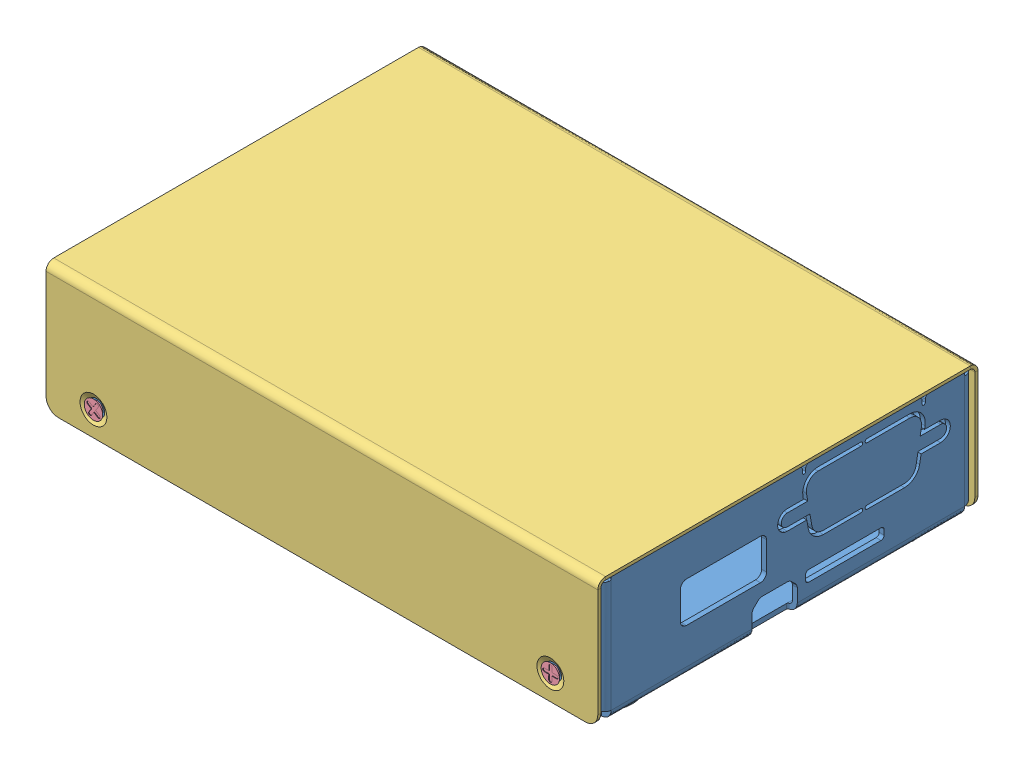
SolidWorks assembly BB100_assembly, configuration Default. Lengths in mm.
Overall size (89.98 22.52 61.99).
15 component instances, 5 part files, 15 mates.
Components (placement in the parent):
- Chassis_bottom_assembly-1: Chassis_bottom_assembly [Default] at (37.4875 44.5592 71.6982) size (89.97 20.42 60.79)
  - Chassis_bottom-1: Chassis_bottom [Default] at (34.5147 38.3972 77.4532) size (89.97 20.42 60.79)
  - Chassis_PEM-1: Chassis_PEM [Default] at (72.1997 37.5972 56.4982) size (7.39 5 6.4)
  - Chassis_PEM-2: Chassis_PEM [Default] at (72.1997 37.5972 98.4082) size (7.39 5 6.4)
  - Chassis_PEM-3: Chassis_PEM [Default] at (6.1597 37.5972 53.3232) size (7.39 5 6.4)
  - Chassis_PEM-4: Chassis_PEM [Default] at (6.1597 37.5972 101.5832) size (7.39 5 6.4)
- Chassis_top-8: Chassis_top [Default] at (72.0021 103.0764 149.1514) size (89.98 20.92 61.99)
- M2_screw-2: M2_screw [Default] at (34.7521 86.1564 121.0564) x (0.254964 -0.966951 0) z (0.966951 0.254964 0) size (3 2.9 3)
- M2_screw-3: M2_screw [Default] at (109.2521 86.1564 121.0564) x (0.254964 -0.966951 0) z (0.966951 0.254964 0) size (3 2.9 3)
- M2_screw-5: M2_screw [Default] at (109.2521 86.1564 177.2464) x (0.014337 0.999897 0) z (0.999897 -0.014337 0) size (3 2.9 3)
- M2_screw-6: M2_screw [Default] at (34.7521 86.1564 177.2464) x (-0.547784 -0.83662 0) z (-0.83662 0.547784 0) size (3 2.9 3)
- Rubber_foot-1: Rubber_foot [Default] at (109.5125 82.0564 126.1051) x (0.5863 0 0.810094) z (0.810094 0 -0.5863) size (10 1.6 10)
- Rubber_foot-2: Rubber_foot [Default] at (109.6402 82.0564 172.1504) x (-0.113067 0 0.993587) z (0.993587 0 0.113067) size (10 1.6 10)
- Rubber_foot-3: Rubber_foot [Default] at (34.3212 82.0564 172.1594) x (-0.113067 0 0.993587) z (0.993587 0 0.113067) size (10 1.6 10)
- Rubber_foot-4: Rubber_foot [Default] at (34.197 82.0564 126.1176) x (-0.113067 0 0.993587) z (0.993587 0 0.113067) size (10 1.6 10)
Mates (geometry in assembly coordinates):
- Concentric1: concentric aligned: circle of Chassis_top-8; cylinder of M2_screw-6 through (34.7521 86.1564 177.2464) axis (0 0 -1) radius 0.97
- Concentric2: concentric aligned: circle of Chassis_top-8; cylinder of M2_screw-5 through (109.2521 86.1564 177.2464) axis (0 0 -1) radius 0.97
- Coincident1: coincident aligned: plane of M2_screw-5 through (109.2521 86.1564 180.1464) normal (0 0 1); plane of M2_screw-6 through (34.7521 86.1564 180.1464) normal (0 0 1)
- Coincident2: coincident aligned: plane of M2_screw-2 through (34.7521 86.1564 118.1564) normal (0 0 -1); plane of M2_screw-3 through (109.2521 86.1564 118.1564) normal (0 0 -1)
- Concentric3: concentric aligned: circle of Chassis_top-8; cylinder of M2_screw-2 through (34.7521 86.1564 121.0564) axis (0 0 1) radius 0.97
- Concentric4: concentric aligned: circle of Chassis_top-8; cylinder of M2_screw-3 through (109.2521 86.1564 121.0564) axis (0 0 1) radius 0.97
- Coincident3: coincident aligned: plane of Chassis_top-8 through (72.0021 103.0764 118.1564) normal (0 0 -1); plane of M2_screw-3 through (109.2521 86.1564 118.1564) normal (0 0 -1)
- Coincident4: coincident aligned: plane of Chassis_top-8 through (72.0021 103.0764 180.1464) normal (0 0 1); plane of M2_screw-5 through (109.2521 86.1564 180.1464) normal (0 0 1)
- Concentric5: concentric aligned: circle of Chassis_bottom_assembly-1/Chassis_bottom-1; circle of Chassis_top-8
- Concentric6: concentric aligned: circle of Chassis_bottom_assembly-1/Chassis_bottom-1; circle of Chassis_top-8
- Distance1: distance = 0.1 mm anti-aligned: plane of Chassis_top-8 through (72.0021 103.0764 179.6464) normal (0 0 -1); plane of Chassis_bottom_assembly-1/Chassis_bottom-1 through (72.0021 82.9564 179.5464) normal (0 0 1)
- Coincident6: coincident aligned: plane of Rubber_foot-3 through (34.3212 80.5564 172.1594) normal (0 -1 0); plane of Rubber_foot-4 through (34.197 80.5564 126.1176) normal (0 -1 0)
- Coincident7: coincident aligned: plane of Rubber_foot-1 through (109.5125 80.5564 126.1051) normal (0 -1 0); plane of Rubber_foot-4 through (34.197 80.5564 126.1176) normal (0 -1 0)
- Coincident8: coincident aligned: plane of Rubber_foot-2 through (109.6402 80.5564 172.1504) normal (0 -1 0); plane of Rubber_foot-4 through (34.197 80.5564 126.1176) normal (0 -1 0)
- Coincident9: coincident anti-aligned: plane of Chassis_bottom_assembly-1/Chassis_bottom-1 through (72.0021 82.1564 149.1514) normal (0 -1 0); plane of Rubber_foot-3 through (34.3212 82.1564 172.1594) normal (0 1 0)
